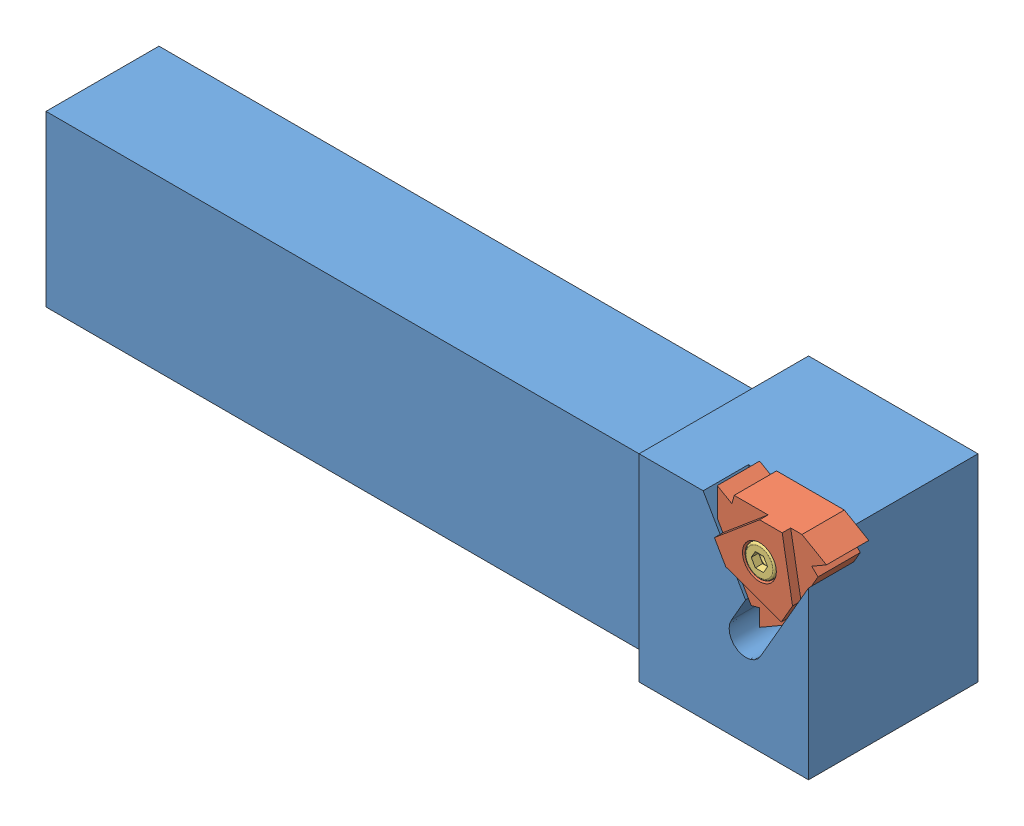
SolidWorks assembly 螺纹刀, configuration 默认. Lengths in mm.
Overall size (136.42 44.29 31).
3 component instances, 3 part files, 5 mates.
Components (placement in the parent):
- 螺纹刀刀柄-1: 螺纹刀刀柄 [默认] at (-16.4578 2.7309 -10) size (130 35 30)
- 螺纹刀刀片-4: 螺纹刀刀片 [默认] at (72.0821 -15.7156 7) x (0.5 -0.866025 0) z (0 0 1) size (19.33 17.99 9)
- hexagon socket head cap screws gb2-1: hexagon socket head cap screws gb2 [GB_FASTENER_SCREWS_HSHCS M3X5-N] at (60.8427 17.7759 16) x (0 0 -1) z (1 0 0) size (8 5.5 5.5)
Mates (geometry in assembly coordinates):
- 重合1: coincident anti-aligned: plane of 螺纹刀刀柄-1 through (61.8983 5.6477 7) normal (-0.866025 0.5 0); plane of 螺纹刀刀片-4 through (63.7099 8.7855 16) normal (0.866025 -0.5 0)
- 重合2: coincident anti-aligned: plane of 螺纹刀刀柄-1 through (57.385 9.7405 7) normal (0.866025 0.5 0); plane of 螺纹刀刀片-4 through (51.8798 19.2759 16) normal (-0.866025 -0.5 0)
- 重合3: coincident anti-aligned: plane of 螺纹刀刀柄-1 through (57.4636 3.9216 7) normal (0 0 1); plane of 螺纹刀刀片-4 through (72.0821 -15.7156 7) normal (0 0 -1)
- 同心1: concentric aligned: cylinder of 螺纹刀刀片-4 through (60.8427 17.7759 16) axis (0 0 1) radius 1.5; cylinder of hexagon socket head cap screws gb-1 through (60.8427 17.7759 8) axis (0 0 1) radius 1.5
- 重合4: coincident anti-aligned: plane of 螺纹刀刀片-4 through (61.5927 16.4768 13) normal (0 0 1); plane of hexagon socket head cap screws gb-1 through (60.8427 17.7759 13) normal (0 0 -1)
